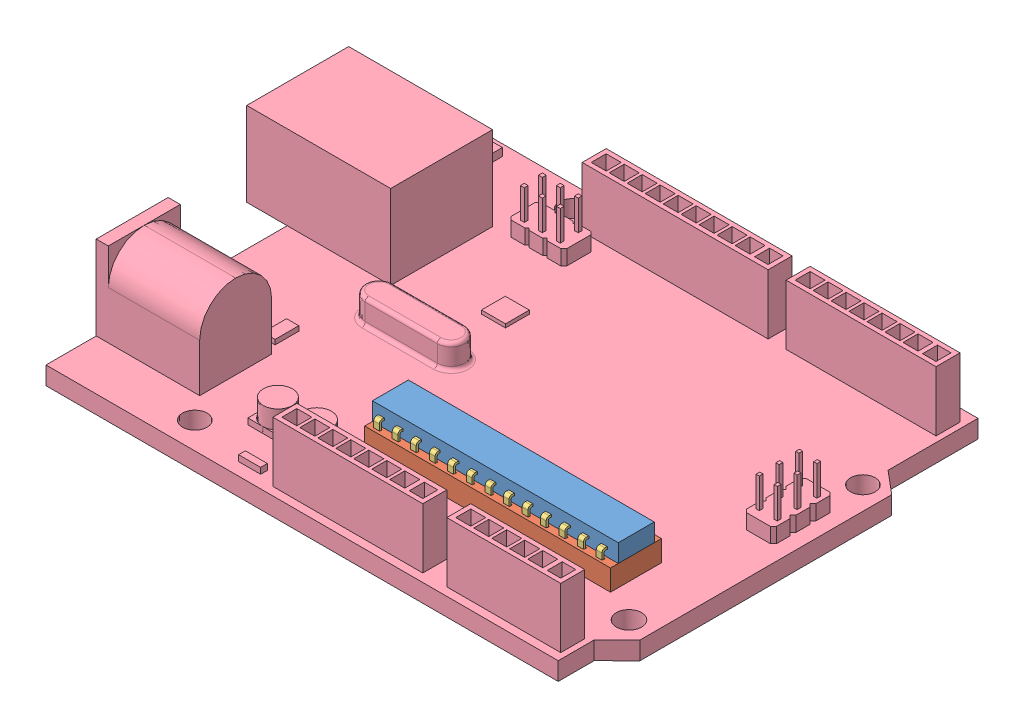
SolidWorks assembly Assem2, configuration Default. Lengths in mm.
Overall size (95.99 17 70).
30 component instances, 5 part files, 32 mates.
Components (placement in the parent):
- part 4-1: part 4 [Default] at (3.2153 22.1562 37.3337) size (41 3 6)
- part 3-1: part 3 [Default] at (3.2153 18.6562 44.6311) size (41 3.5 8.5)
- part 5-2: part 5 [Default] at (5.1653 23.6562 44.1285) x (0 0 1) z (-1 0 0) size (1.9 4.05 0.95)
- Part2^Assem2-1: Part2^Assem2 [Default] at origin (virtual)
- part 5-3: part 5 [Default] at (4.2132 23.6562 36.521) x (0 0 -1) z (1 0 0) size (1.9 4.05 0.95)
- part 5-4: part 5 [Default] at (8.2653 23.6403 44.1372) x (0 0 1) z (-1 0 0) size (1.9 4.05 0.95)
- part 5-5: part 5 [Default] at (11.3653 23.6329 44.1752) x (0 0 1) z (-1 0 0) size (1.9 4.05 0.95)
- part 5-6: part 5 [Default] at (14.4653 23.6363 44.1281) x (0 0 1) z (-1 0 0) size (1.9 4.05 0.95)
- part 5-7: part 5 [Default] at (17.5653 23.6278 44.201) x (0 0 1) z (-1 0 0) size (1.9 4.05 0.95)
- part 5-8: part 5 [Default] at (20.6653 23.6426 44.168) x (0 0 1) z (-1 0 0) size (1.9 4.05 0.95)
- part 5-9: part 5 [Default] at (23.7653 23.6427 44.1305) x (0 0 1) z (-1 0 0) size (1.9 4.05 0.95)
- part 5-10: part 5 [Default] at (26.8653 23.6423 44.1992) x (0 0 1) z (-1 0 0) size (1.9 4.05 0.95)
- part 5-11: part 5 [Default] at (29.9653 23.6442 44.1584) x (0 0 1) z (-1 0 0) size (1.9 4.05 0.95)
- part 5-12: part 5 [Default] at (33.0653 23.6614 44.208) x (0 0 1) z (-1 0 0) size (1.9 4.05 0.95)
- part 5-13: part 5 [Default] at (36.1653 23.6562 44.2067) x (0 0 1) z (-1 0 0) size (1.9 4.05 0.95)
- part 5-14: part 5 [Default] at (39.2653 23.6625 44.1953) x (0 0 1) z (-1 0 0) size (1.9 4.05 0.95)
- part 5-15: part 5 [Default] at (42.3653 23.6667 44.2129) x (0 0 1) z (-1 0 0) size (1.9 4.05 0.95)
- part 5-16: part 5 [Default] at (7.3132 23.6299 36.5424) x (0 0 -1) z (1 0 0) size (1.9 4.05 0.95)
- part 5-17: part 5 [Default] at (10.4132 23.6658 36.5642) x (0 0 -1) z (1 0 0) size (1.9 4.05 0.95)
- part 5-18: part 5 [Default] at (13.5132 23.6527 36.5738) x (0 0 -1) z (1 0 0) size (1.9 4.05 0.95)
- part 5-19: part 5 [Default] at (16.6132 23.6749 36.5975) x (0 0 -1) z (1 0 0) size (1.9 4.05 0.95)
- part 5-20: part 5 [Default] at (19.7132 23.6547 36.6122) x (0 0 -1) z (1 0 0) size (1.9 4.05 0.95)
- part 5-21: part 5 [Default] at (22.8132 23.6873 36.5706) x (0 0 -1) z (1 0 0) size (1.9 4.05 0.95)
- part 5-22: part 5 [Default] at (25.9132 23.679 36.5914) x (0 0 -1) z (1 0 0) size (1.9 4.05 0.95)
- part 5-23: part 5 [Default] at (29.0132 23.6707 36.586) x (0 0 -1) z (1 0 0) size (1.9 4.05 0.95)
- part 5-24: part 5 [Default] at (32.1132 23.6471 36.5658) x (0 0 -1) z (1 0 0) size (1.9 4.05 0.95)
- part 5-25: part 5 [Default] at (35.2132 23.6438 36.6085) x (0 0 -1) z (1 0 0) size (1.9 4.05 0.95)
- part 5-26: part 5 [Default] at (38.3132 23.6674 36.6051) x (0 0 -1) z (1 0 0) size (1.9 4.05 0.95)
- part 5-27: part 5 [Default] at (41.4132 23.6419 36.5711) x (0 0 -1) z (1 0 0) size (1.9 4.05 0.95)
- Part2-1: Part2 [Default] at (-50.2541 15.6562 58.8796) x (1 0 0) z (0 1 0) size (95.99 70 17)
Mates (geometry in assembly coordinates):
- Coincident1: coincident anti-aligned: plane of part 4-1 through (3.2153 22.1562 37.3337) normal (0 -1 0); plane of part 3-1 through (3.2153 22.1562 44.6311) normal (0 1 0)
- Coincident2: coincident aligned: plane of part 4-1 through (44.2153 25.1562 37.3337) normal (1 0 0); plane of part 3-1 through (44.2153 22.1562 44.6311) normal (1 0 0)
- Coincident7: coincident anti-aligned: plane of part 4-1 through (4.2153 23.6562 41.8337) normal (1 0 0); plane of part 5-2 through (4.2153 23.6562 44.1285) normal (-1 0 0)
- Coincident8: coincident anti-aligned: plane of part 4-1 through (4.2153 23.6562 41.8337) normal (0 -1 0); plane of part 5-2 through (4.2153 23.6562 44.1285) normal (0 1 0)
- Coincident9: coincident anti-aligned: plane of part 4-1 through (4.2132 23.6562 38.8337) normal (1 0 0); plane of part 5-3 through (4.2132 23.6562 36.521) normal (-1 0 0)
- Coincident10: coincident anti-aligned: plane of part 4-1 through (4.2132 23.6562 38.8337) normal (0 -1 0); plane of part 5-3 through (5.1632 23.6562 36.521) normal (0 1 0)
- Coincident11: coincident anti-aligned: plane of part 3-1 through (7.3153 19.1562 44.1311) normal (1 0 0); plane of part 5-4 through (7.3153 23.6403 44.1372) normal (-1 0 0)
- Coincident12: coincident anti-aligned: plane of part 3-1 through (10.4153 19.1562 44.1311) normal (1 0 0); plane of part 5-5 through (10.4153 23.6329 44.1752) normal (-1 0 0)
- Coincident13: coincident anti-aligned: plane of part 3-1 through (13.5153 19.1562 44.1311) normal (1 0 0); plane of part 5-6 through (13.5153 23.6363 44.1281) normal (-1 0 0)
- Coincident14: coincident anti-aligned: plane of part 3-1 through (16.6153 19.1562 44.1311) normal (1 0 0); plane of part 5-7 through (16.6153 23.6278 44.201) normal (-1 0 0)
- Coincident15: coincident anti-aligned: plane of part 3-1 through (19.7153 19.1562 44.1311) normal (1 0 0); plane of part 5-8 through (19.7153 23.6426 44.168) normal (-1 0 0)
- Coincident16: coincident anti-aligned: plane of part 3-1 through (22.8153 19.1562 44.1311) normal (1 0 0); plane of part 5-9 through (22.8153 23.6427 44.1305) normal (-1 0 0)
- Coincident17: coincident anti-aligned: plane of part 3-1 through (25.9153 19.1562 44.1311) normal (1 0 0); plane of part 5-10 through (25.9153 23.6423 44.1992) normal (-1 0 0)
- Coincident18: coincident anti-aligned: plane of part 3-1 through (29.0153 19.1562 44.1311) normal (1 0 0); plane of part 5-11 through (29.0153 23.6442 44.1584) normal (-1 0 0)
- Coincident19: coincident anti-aligned: plane of part 3-1 through (32.1153 19.1562 44.1311) normal (1 0 0); plane of part 5-12 through (32.1153 23.6614 44.208) normal (-1 0 0)
- Coincident21: coincident anti-aligned: plane of part 3-1 through (35.2153 19.1562 44.1311) normal (1 0 0); plane of part 5-13 through (35.2153 23.6562 44.2067) normal (-1 0 0)
- Coincident23: coincident anti-aligned: plane of part 4-1 through (35.2153 23.6562 41.8337) normal (0 -1 0); plane of part 5-13 through (35.2153 23.6562 44.2067) normal (0 1 0)
- Coincident24: coincident anti-aligned: plane of part 3-1 through (38.3153 19.1562 44.1311) normal (1 0 0); plane of part 5-14 through (38.3153 23.6625 44.1953) normal (-1 0 0)
- Coincident25: coincident anti-aligned: plane of part 3-1 through (41.4153 19.1562 44.1311) normal (1 0 0); plane of part 5-15 through (41.4153 23.6667 44.2129) normal (-1 0 0)
- Coincident28: coincident anti-aligned: plane of part 4-1 through (7.3132 23.6562 38.8337) normal (1 0 0); plane of part 5-16 through (7.3132 23.6299 36.5424) normal (-1 0 0)
- Coincident29: coincident anti-aligned: plane of part 4-1 through (10.4132 23.6562 38.8337) normal (1 0 0); plane of part 5-17 through (10.4132 23.6658 36.5642) normal (-1 0 0)
- Coincident30: coincident anti-aligned: plane of part 4-1 through (13.5132 23.6562 38.8337) normal (1 0 0); plane of part 5-18 through (13.5132 23.6527 36.5738) normal (-1 0 0)
- Coincident31: coincident anti-aligned: plane of part 4-1 through (16.6132 23.6562 38.8337) normal (1 0 0); plane of part 5-19 through (16.6132 23.6749 36.5975) normal (-1 0 0)
- Coincident32: coincident anti-aligned: plane of part 4-1 through (19.7132 23.6562 38.8337) normal (1 0 0); plane of part 5-20 through (19.7132 23.6547 36.6122) normal (-1 0 0)
- Coincident33: coincident anti-aligned: plane of part 4-1 through (22.8132 23.6562 38.8337) normal (1 0 0); plane of part 5-21 through (22.8132 23.6873 36.5706) normal (-1 0 0)
- Coincident34: coincident anti-aligned: plane of part 4-1 through (25.9132 23.6562 38.8337) normal (1 0 0); plane of part 5-22 through (25.9132 23.679 36.5914) normal (-1 0 0)
- Coincident35: coincident anti-aligned: plane of part 4-1 through (29.0132 23.6562 38.8337) normal (1 0 0); plane of part 5-23 through (29.0132 23.6707 36.586) normal (-1 0 0)
- Coincident36: coincident anti-aligned: plane of part 4-1 through (32.1132 23.6562 38.8337) normal (1 0 0); plane of part 5-24 through (32.1132 23.6471 36.5658) normal (-1 0 0)
- Coincident37: coincident anti-aligned: plane of part 4-1 through (35.2132 23.6562 38.8337) normal (1 0 0); plane of part 5-25 through (35.2132 23.6438 36.6085) normal (-1 0 0)
- Coincident38: coincident anti-aligned: plane of part 4-1 through (38.3132 23.6562 38.8337) normal (1 0 0); plane of part 5-26 through (38.3132 23.6674 36.6051) normal (-1 0 0)
- Coincident39: coincident anti-aligned: plane of part 4-1 through (41.4132 23.6562 38.8337) normal (1 0 0); plane of part 5-27 through (41.4132 23.6419 36.5711) normal (-1 0 0)
- Coincident40: coincident anti-aligned: plane of part 3-1 through (3.2153 18.6562 44.6311) normal (0 -1 0); plane of Part2-1 through (-50.2541 18.6562 58.8796) normal (0 1 0)
